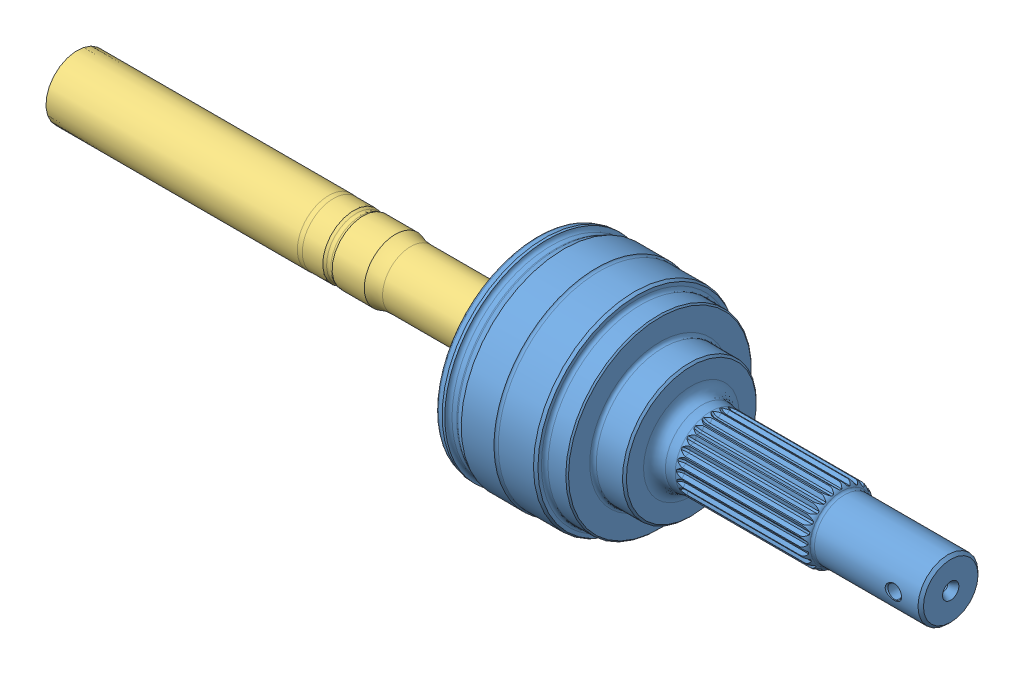
SolidWorks assembly OBKIT AC1700i, configuration Default. Lengths in mm.
Overall size (319.88 75.2 75.2).
4 component instances, 4 part files, 0 mates.
Components (placement in the parent):
- 10274392 AC Outer Race_1-1: 10274392 AC Outer Race_1 [Default] at origin size (151.63 75.2 75.2)
- AC1700i Inner Race-1: AC1700i Inner Race [Default] at (17.63 0 0) x (0 -0.065984 0.997821) z (1 0 0) size (55.56 55.56 20.2)
- AC1700i Bar End-1: AC1700i Bar End [Default] at (31.75 0 0) x (-1 0 0) z (0 0.997821 0.065984) size (200 23.5 23.5)
- AC1700i Circlip-1: AC1700i Circlip [Default] at (22.35 0 0) x (1 0 0) z (0 -0.684669 -0.728854) size (1.5 21.02 23.81)
